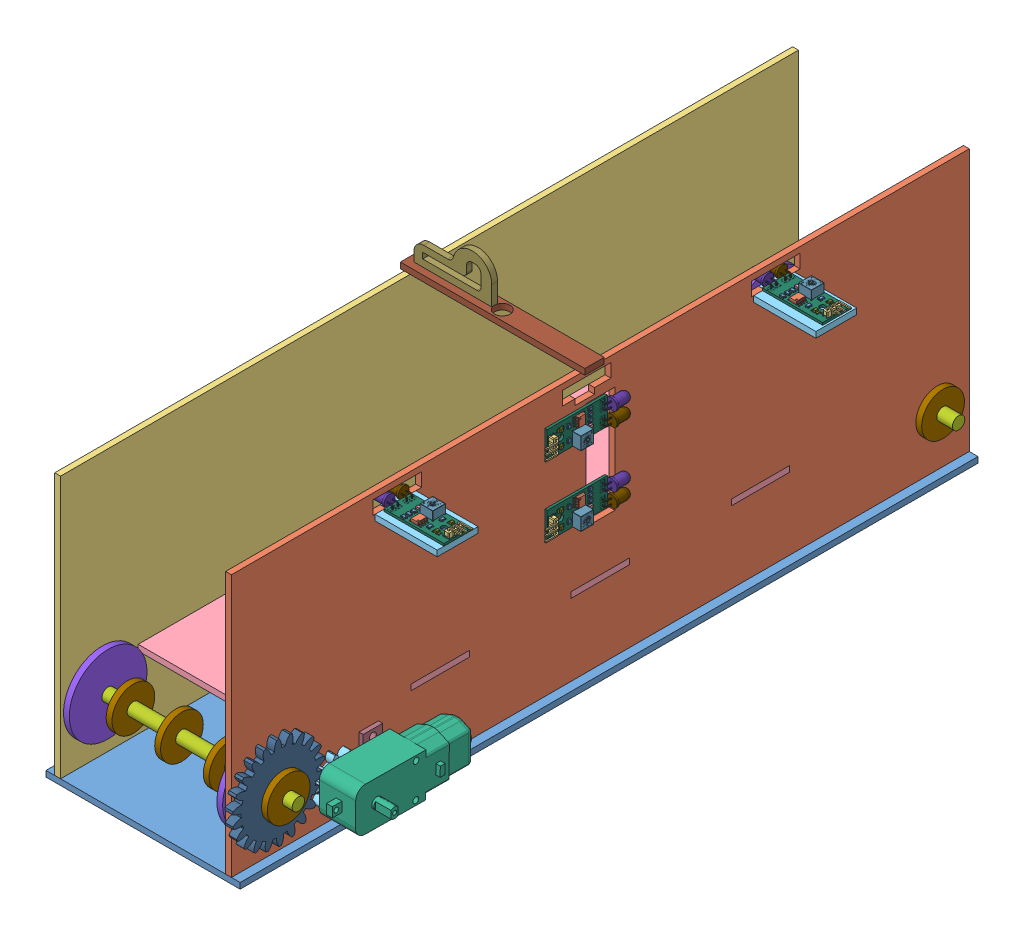
SolidWorks assembly EnsambleSoloIr, configuration Predeterminado. Lengths in mm.
Overall size (132.68 161.82 399.89).
100 component instances, 41 part files, 61 mates.
Components (placement in the parent):
- BAseGeneral-1: BAseGeneral [Predeterminado] at (-4.2266 -31.7563 350) size (100 3 380)
- ParedDerecha-2: ParedDerecha [Predeterminado] at (38.2734 38.7437 350) x (0 0 -1) z (1 0 0) size (380 138 3)
- ParedIzquierda-1: ParedIzquierda [Predeterminado] at (-46.7266 38.7437 350) x (0 0 1) z (-1 0 0) size (380 138 3)
- base-1: base [Predeterminado] at (-4.2266 8.2437 350) size (91 3 300)
- MiEngranePequeñoV2-1: MiEngranePequeñoV2 [Predeterminado] at (41.7734 384.4008 222.5284) x (0 -0.999961 0.008878) z (0 0.008878 0.999961) size (23.7 4 23.48)
- Motor-1: Motor [Predeterminado] at (65.5434 -8.5781 489.3215) x (0 -0.008878 -0.999961) z (0 0.999961 -0.008878) size (70.2 36.87 22.3)
- ejeRuedas-1: ejeRuedas [Predeterminado] at (55.7734 1.2437 520) x (0 1 0) z (0 0 1) size (6.4 110 6.4)
- RuedaGrande-1: RuedaGrande [Predeterminado] at (-42.2266 1.2437 520) x (0 1 0) z (0 0 1) size (40 3 40)
- RuedaGrande-2: RuedaGrande [Predeterminado] at (36.7734 1.2437 520) x (0 1 0) z (0 0 1) size (40 3 40)
- ruedaPequeña-1: ruedaPequeña [Predeterminado] at (-29.2266 1.2437 520) x (0 1 0) z (0 0 1) size (22 3 22)
- ruedaPequeña-2: ruedaPequeña [Predeterminado] at (-4.2266 1.2437 520) x (0 1 0) z (0 0 1) size (22 3 22)
- ruedaPequeña-3: ruedaPequeña [Predeterminado] at (20.7734 1.2437 520) x (0 1 0) z (0 0 1) size (22 3 22)
- EngraneGrande-1: EngraneGrande [Predeterminado] at (41.7734 -30.0906 1041.862) x (0 0.673646 -0.739054) z (1 0 0) size (48.01 47.68 4)
- ruedaPequeña-4: ruedaPequeña [Predeterminado] at (47.7734 1.2437 520) x (0 -1 0) z (0 0 1) size (22 3 22)
- ruedaPequeña-5: ruedaPequeña [Predeterminado] at (-53.2266 1.2437 520) x (0 -1 0) z (0 0 1) size (22 3 22)
- ejeRuedas-2: ejeRuedas [Predeterminado] at (55.7734 1.2437 180) x (0 1 0) z (0 0 1) size (6.4 110 6.4)
- ruedaPequeña-6: ruedaPequeña [Predeterminado] at (-50.2266 1.2437 180) x (0 1 0) z (0 0 1) size (22 3 22)
- ruedaPequeña-7: ruedaPequeña [Predeterminado] at (-4.2266 1.2437 180) x (0 1 0) z (0 0 1) size (22 3 22)
- ruedaPequeña-8: ruedaPequeña [Predeterminado] at (20.7734 1.2437 180) x (0 1 0) z (0 0 1) size (22 3 22)
- RuedaGrande-3: RuedaGrande [Predeterminado] at (-41.2266 1.2437 180) x (0 1 0) z (0 0 1) size (40 3 40)
- RuedaGrande-4: RuedaGrande [Predeterminado] at (32.7734 1.2437 180) x (0 -0.381849 0.924225) z (0 0.924225 0.381849) size (40 3 40)
- ruedaPequeña-9: ruedaPequeña [Predeterminado] at (47.7734 1.2437 180) x (0 1 0) z (0 0 1) size (22 3 22)
- ruedaPequeña-10: ruedaPequeña [Predeterminado] at (-29.2266 1.2437 180) x (0 1 0) z (0 0 1) size (22 3 22)
- Travesaño-1: Travesaño [Predeterminado] at (-4.2266 106.2437 355) size (95 3 10)
- GuiaMangera-1: GuiaMangera [Predeterminado] at (-28.1798 119.2437 353.5) size (40 23 3)
- SoporteMotor-1: SoporteMotor [Predeterminado] at (40.445 -8.7563 469.3) x (0 0 -1) z (1 0 0) size (10 24 3)
- Sensor_IR.stp-1: Sensor_IR.stp [Predeterminado] at (41.6734 48.2437 363.5) x (0 0 -1) z (1 0 0) size (45.22 14 7.87)
  - 3362P-1-102LF.stp-1: 3362P-1-102LF.stp [Predeterminado] at (0.5 -3.2 1.53) x (1 0 0) z (0 -1 0) size (6.6 7.58 6.6)
  - IR_Sensor_FC-51_1.stp-1: IR_Sensor_FC-51_1.stp [Predeterminado] at origin size (31 14 1.25)
  - KPTR-3216CGCK.stp-1: KPTR-3216CGCK.stp [Predeterminado] at (-8.7 3.8 1.45) x (1 0 0) z (0 0 -1) size (3.2 1.6 1.05)
  - KPTR-3216CGCK.stp-2: KPTR-3216CGCK.stp [Predeterminado] at (-8.7 -3.8 1.45) x (1 0 0) z (0 0 -1) size (3.2 1.6 1.05)
  - LED 5mm.stp-1: LED 5mm.stp [Predeterminado] at (15.74 3.64 3) x (0 1 0) z (1 0 0) size (5.5 6.7 11.78)
  - LED 5mm_foto.stp-1: LED 5mm_foto.stp [Predeterminado] at (15.74 -3.64 3) x (0 1 0) z (1 0 0) size (5.5 6.7 11.78)
  - RESC-0805.stp-1: RESC-0805.stp [Predeterminado] at (-4.525 -3.15 1.2) x (0 -1 0) z (0 0 1) size (2.1 1.35 0.6)
  - RESC-0805.stp-2: RESC-0805.stp [Predeterminado] at (-4.525 3.25 1.2) x (0 1 0) z (0 0 1) size (2.1 1.35 0.6)
  - SOIC8-150-50.stp-1: SOIC8-150-50.stp [Predeterminado] at (0.55 3.85 1.2) x (1 0 0) z (0 -1 0) size (6 1.91 4.9)
  - 1 Pin 2.54 mm Right Angle Single Row Pin Header Male 90 degrees Needle Connector.stp-1: 1 Pin 2.54 mm Right Angle Single Row Pin Header Male 90 degrees Needle Connector.stp [Predeterminado] at (-13.5 2.54 -1.76) x (-1 0 0) z (0 0 1) size (8.45 2.54 7.3)
  - 1 Pin 2.54 mm Right Angle Single Row Pin Header Male 90 degrees Needle Connector.stp-2: 1 Pin 2.54 mm Right Angle Single Row Pin Header Male 90 degrees Needle Connector.stp [Predeterminado] at (-13.5 0 -1.76) x (-1 0 0) z (0 0 1) size (8.45 2.54 7.3)
  - 1 Pin 2.54 mm Right Angle Single Row Pin Header Male 90 degrees Needle Connector.stp-3: 1 Pin 2.54 mm Right Angle Single Row Pin Header Male 90 degrees Needle Connector.stp [Predeterminado] at (-13.5 -2.54 -1.76) x (-1 0 0) z (0 0 1) size (8.45 2.54 7.3)
  - RESC-0805.stp-3: RESC-0805.stp [Predeterminado] at (6.45 5.625 1.2) size (2.1 1.35 0.6)
  - RESC-0805.stp-4: RESC-0805.stp [Predeterminado] at (6.45 3.085 1.2) size (2.1 1.35 0.6)
  - RESC-0805.stp-5: RESC-0805.stp [Predeterminado] at (6.45 0.545 1.2) size (2.1 1.35 0.6)
  - CAPC-0805-T0.95-BN.stp-1: CAPC-0805-T0.95-BN.stp [Predeterminado] at (6.45 -1.995 1.2) size (2.1 1.35 0.95)
  - CAPC-0805-T0.95-BN.stp-2: CAPC-0805-T0.95-BN.stp [Predeterminado] at (6.45 -4.535 1.2) size (2.1 1.35 0.95)
- Sensor_IR.stp-2: Sensor_IR.stp [Predeterminado] at (41.6734 84.2437 363.5) x (0 0 -1) z (1 0 0) size (45.22 14 7.87)
  - 3362P-1-102LF.stp-1: 3362P-1-102LF.stp [Predeterminado] at (0.5 -3.2 1.53) x (1 0 0) z (0 -1 0) size (6.6 7.58 6.6)
  - IR_Sensor_FC-51_1.stp-1: IR_Sensor_FC-51_1.stp [Predeterminado] at origin size (31 14 1.25)
  - KPTR-3216CGCK.stp-1: KPTR-3216CGCK.stp [Predeterminado] at (-8.7 3.8 1.45) x (1 0 0) z (0 0 -1) size (3.2 1.6 1.05)
  - KPTR-3216CGCK.stp-2: KPTR-3216CGCK.stp [Predeterminado] at (-8.7 -3.8 1.45) x (1 0 0) z (0 0 -1) size (3.2 1.6 1.05)
  - LED 5mm.stp-1: LED 5mm.stp [Predeterminado] at (15.74 3.64 3) x (0 1 0) z (1 0 0) size (5.5 6.7 11.78)
  - LED 5mm_foto.stp-1: LED 5mm_foto.stp [Predeterminado] at (15.74 -3.64 3) x (0 1 0) z (1 0 0) size (5.5 6.7 11.78)
  - RESC-0805.stp-1: RESC-0805.stp [Predeterminado] at (-4.525 -3.15 1.2) x (0 -1 0) z (0 0 1) size (2.1 1.35 0.6)
  - RESC-0805.stp-2: RESC-0805.stp [Predeterminado] at (-4.525 3.25 1.2) x (0 1 0) z (0 0 1) size (2.1 1.35 0.6)
  - SOIC8-150-50.stp-1: SOIC8-150-50.stp [Predeterminado] at (0.55 3.85 1.2) x (1 0 0) z (0 -1 0) size (6 1.91 4.9)
  - 1 Pin 2.54 mm Right Angle Single Row Pin Header Male 90 degrees Needle Connector.stp-1: 1 Pin 2.54 mm Right Angle Single Row Pin Header Male 90 degrees Needle Connector.stp [Predeterminado] at (-13.5 2.54 -1.76) x (-1 0 0) z (0 0 1) size (8.45 2.54 7.3)
  - 1 Pin 2.54 mm Right Angle Single Row Pin Header Male 90 degrees Needle Connector.stp-2: 1 Pin 2.54 mm Right Angle Single Row Pin Header Male 90 degrees Needle Connector.stp [Predeterminado] at (-13.5 0 -1.76) x (-1 0 0) z (0 0 1) size (8.45 2.54 7.3)
  - 1 Pin 2.54 mm Right Angle Single Row Pin Header Male 90 degrees Needle Connector.stp-3: 1 Pin 2.54 mm Right Angle Single Row Pin Header Male 90 degrees Needle Connector.stp [Predeterminado] at (-13.5 -2.54 -1.76) x (-1 0 0) z (0 0 1) size (8.45 2.54 7.3)
  - RESC-0805.stp-3: RESC-0805.stp [Predeterminado] at (6.45 5.625 1.2) size (2.1 1.35 0.6)
  - RESC-0805.stp-4: RESC-0805.stp [Predeterminado] at (6.45 3.085 1.2) size (2.1 1.35 0.6)
  - RESC-0805.stp-5: RESC-0805.stp [Predeterminado] at (6.45 0.545 1.2) size (2.1 1.35 0.6)
  - CAPC-0805-T0.95-BN.stp-1: CAPC-0805-T0.95-BN.stp [Predeterminado] at (6.45 -1.995 1.2) size (2.1 1.35 0.95)
  - CAPC-0805-T0.95-BN.stp-2: CAPC-0805-T0.95-BN.stp [Predeterminado] at (6.45 -4.535 1.2) size (2.1 1.35 0.95)
- SoporteIrHorizontal-1: SoporteIrHorizontal [Predeterminado] at (38.2734 93.2437 460.5) x (0 0 -1) z (1 0 0) size (21 3 35)
- SoporteIrHorizontal-2: SoporteIrHorizontal [Predeterminado] at (38.2734 93.2437 265.5) x (0 0 -1) z (1 0 0) size (21 3 35)
- Sensor_IR.stp-3: Sensor_IR.stp [Predeterminado] at (57.7734 97.2437 260.5) x (-1 0 0) z (0 1 0) size (45.22 14 7.87)
  - 3362P-1-102LF.stp-1: 3362P-1-102LF.stp [Predeterminado] at (0.5 -3.2 1.53) x (1 0 0) z (0 -1 0) size (6.6 7.58 6.6)
  - IR_Sensor_FC-51_1.stp-1: IR_Sensor_FC-51_1.stp [Predeterminado] at origin size (31 14 1.25)
  - KPTR-3216CGCK.stp-1: KPTR-3216CGCK.stp [Predeterminado] at (-8.7 3.8 1.45) x (1 0 0) z (0 0 -1) size (3.2 1.6 1.05)
  - KPTR-3216CGCK.stp-2: KPTR-3216CGCK.stp [Predeterminado] at (-8.7 -3.8 1.45) x (1 0 0) z (0 0 -1) size (3.2 1.6 1.05)
  - LED 5mm.stp-1: LED 5mm.stp [Predeterminado] at (15.74 3.64 3) x (0 1 0) z (1 0 0) size (5.5 6.7 11.78)
  - LED 5mm_foto.stp-1: LED 5mm_foto.stp [Predeterminado] at (15.74 -3.64 3) x (0 1 0) z (1 0 0) size (5.5 6.7 11.78)
  - RESC-0805.stp-1: RESC-0805.stp [Predeterminado] at (-4.525 -3.15 1.2) x (0 -1 0) z (0 0 1) size (2.1 1.35 0.6)
  - RESC-0805.stp-2: RESC-0805.stp [Predeterminado] at (-4.525 3.25 1.2) x (0 1 0) z (0 0 1) size (2.1 1.35 0.6)
  - SOIC8-150-50.stp-1: SOIC8-150-50.stp [Predeterminado] at (0.55 3.85 1.2) x (1 0 0) z (0 -1 0) size (6 1.91 4.9)
  - 1 Pin 2.54 mm Right Angle Single Row Pin Header Male 90 degrees Needle Connector.stp-1: 1 Pin 2.54 mm Right Angle Single Row Pin Header Male 90 degrees Needle Connector.stp [Predeterminado] at (-13.5 2.54 -1.76) x (-1 0 0) z (0 0 1) size (8.45 2.54 7.3)
  - 1 Pin 2.54 mm Right Angle Single Row Pin Header Male 90 degrees Needle Connector.stp-2: 1 Pin 2.54 mm Right Angle Single Row Pin Header Male 90 degrees Needle Connector.stp [Predeterminado] at (-13.5 0 -1.76) x (-1 0 0) z (0 0 1) size (8.45 2.54 7.3)
  - 1 Pin 2.54 mm Right Angle Single Row Pin Header Male 90 degrees Needle Connector.stp-3: 1 Pin 2.54 mm Right Angle Single Row Pin Header Male 90 degrees Needle Connector.stp [Predeterminado] at (-13.5 -2.54 -1.76) x (-1 0 0) z (0 0 1) size (8.45 2.54 7.3)
  - RESC-0805.stp-3: RESC-0805.stp [Predeterminado] at (6.45 5.625 1.2) size (2.1 1.35 0.6)
  - RESC-0805.stp-4: RESC-0805.stp [Predeterminado] at (6.45 3.085 1.2) size (2.1 1.35 0.6)
  - RESC-0805.stp-5: RESC-0805.stp [Predeterminado] at (6.45 0.545 1.2) size (2.1 1.35 0.6)
  - CAPC-0805-T0.95-BN.stp-1: CAPC-0805-T0.95-BN.stp [Predeterminado] at (6.45 -1.995 1.2) size (2.1 1.35 0.95)
  - CAPC-0805-T0.95-BN.stp-2: CAPC-0805-T0.95-BN.stp [Predeterminado] at (6.45 -4.535 1.2) size (2.1 1.35 0.95)
- Sensor_IR.stp-4: Sensor_IR.stp [Predeterminado] at (57.7734 96.2437 455.4997) x (-1 0 -0.000038) z (0 1 0) size (45.22 14 7.87)
  - 3362P-1-102LF.stp-1: 3362P-1-102LF.stp [Predeterminado] at (0.5 -3.2 1.53) x (1 0 0) z (0 -1 0) size (6.6 7.58 6.6)
  - IR_Sensor_FC-51_1.stp-1: IR_Sensor_FC-51_1.stp [Predeterminado] at origin size (31 14 1.25)
  - KPTR-3216CGCK.stp-1: KPTR-3216CGCK.stp [Predeterminado] at (-8.7 3.8 1.45) x (1 0 0) z (0 0 -1) size (3.2 1.6 1.05)
  - KPTR-3216CGCK.stp-2: KPTR-3216CGCK.stp [Predeterminado] at (-8.7 -3.8 1.45) x (1 0 0) z (0 0 -1) size (3.2 1.6 1.05)
  - LED 5mm.stp-1: LED 5mm.stp [Predeterminado] at (15.74 3.64 3) x (0 1 0) z (1 0 0) size (5.5 6.7 11.78)
  - LED 5mm_foto.stp-1: LED 5mm_foto.stp [Predeterminado] at (15.74 -3.64 3) x (0 1 0) z (1 0 0) size (5.5 6.7 11.78)
  - RESC-0805.stp-1: RESC-0805.stp [Predeterminado] at (-4.525 -3.15 1.2) x (0 -1 0) z (0 0 1) size (2.1 1.35 0.6)
  - RESC-0805.stp-2: RESC-0805.stp [Predeterminado] at (-4.525 3.25 1.2) x (0 1 0) z (0 0 1) size (2.1 1.35 0.6)
  - SOIC8-150-50.stp-1: SOIC8-150-50.stp [Predeterminado] at (0.55 3.85 1.2) x (1 0 0) z (0 -1 0) size (6 1.91 4.9)
  - 1 Pin 2.54 mm Right Angle Single Row Pin Header Male 90 degrees Needle Connector.stp-1: 1 Pin 2.54 mm Right Angle Single Row Pin Header Male 90 degrees Needle Connector.stp [Predeterminado] at (-13.5 2.54 -1.76) x (-1 0 0) z (0 0 1) size (8.45 2.54 7.3)
  - 1 Pin 2.54 mm Right Angle Single Row Pin Header Male 90 degrees Needle Connector.stp-2: 1 Pin 2.54 mm Right Angle Single Row Pin Header Male 90 degrees Needle Connector.stp [Predeterminado] at (-13.5 0 -1.76) x (-1 0 0) z (0 0 1) size (8.45 2.54 7.3)
  - 1 Pin 2.54 mm Right Angle Single Row Pin Header Male 90 degrees Needle Connector.stp-3: 1 Pin 2.54 mm Right Angle Single Row Pin Header Male 90 degrees Needle Connector.stp [Predeterminado] at (-13.5 -2.54 -1.76) x (-1 0 0) z (0 0 1) size (8.45 2.54 7.3)
  - RESC-0805.stp-3: RESC-0805.stp [Predeterminado] at (6.45 5.625 1.2) size (2.1 1.35 0.6)
  - RESC-0805.stp-4: RESC-0805.stp [Predeterminado] at (6.45 3.085 1.2) size (2.1 1.35 0.6)
  - RESC-0805.stp-5: RESC-0805.stp [Predeterminado] at (6.45 0.545 1.2) size (2.1 1.35 0.6)
  - CAPC-0805-T0.95-BN.stp-1: CAPC-0805-T0.95-BN.stp [Predeterminado] at (6.45 -1.995 1.2) size (2.1 1.35 0.95)
  - CAPC-0805-T0.95-BN.stp-2: CAPC-0805-T0.95-BN.stp [Predeterminado] at (6.45 -4.535 1.2) size (2.1 1.35 0.95)
Mates (geometry in assembly coordinates):
- Coincidente2: coincident anti-aligned: plane of BAseGeneral-1 through (41.2734 -28.7563 417.5) normal (-1 0 0); plane of ParedDerecha-2 through (41.2734 38.7437 350) normal (1 0 0)
- Coincidente4: coincident anti-aligned: plane of BAseGeneral-1 through (38.2734 -28.7563 447.5) normal (0 0 -1); plane of ParedDerecha-2 through (41.2734 38.7437 447.5) normal (0 0 1)
- Coincidente5: coincident aligned: plane of BAseGeneral-1 through (-4.2266 -31.7563 350) normal (0 -1 0); plane of ParedDerecha-2 through (41.2734 -31.7563 350) normal (0 -1 0)
- Coincidente6: coincident anti-aligned: plane of BAseGeneral-1 through (-49.7266 -28.7563 417.5) normal (1 0 0); plane of ParedIzquierda-1 through (-49.7266 38.7437 350) normal (-1 0 0)
- Coincidente7: coincident anti-aligned: plane of BAseGeneral-1 through (-49.7266 -28.7563 447.5) normal (0 0 -1); plane of ParedIzquierda-1 through (-49.7266 -31.7563 447.5) normal (0 0 1)
- Coincidente8: coincident aligned: plane of BAseGeneral-1 through (-4.2266 -31.7563 350) normal (0 -1 0); plane of ParedIzquierda-1 through (-49.7266 -31.7563 335) normal (0 -1 0)
- Coincidente9: coincident aligned: plane of ParedDerecha-2 through (41.2734 38.7437 350) normal (1 0 0); plane of base-1 through (41.2734 11.2437 447.5) normal (1 0 0)
- Coincidente10: coincident anti-aligned: plane of ParedDerecha-2 through (41.2734 38.7437 447.5) normal (0 0 -1); plane of base-1 through (38.2734 11.2437 447.5) normal (0 0 1)
- Coincidente11: coincident anti-aligned: plane of ParedDerecha-2 through (41.2734 11.2437 350) normal (0 -1 0); plane of base-1 through (-4.2266 11.2437 350) normal (0 1 0)
- Coincidente23: coincident anti-aligned: plane of MiEngranePequeñoV2-1 through (45.7734 386.7548 487.6616) normal (0 -0.008878 -0.999961); plane of Motor-1 through (45.7734 -8.5617 491.1715) normal (0 0.008878 0.999961)
- Coincidente24: coincident anti-aligned: plane of MiEngranePequeñoV2-1 through (45.7734 384.4008 222.5284) normal (1 0 0); plane of Motor-1 through (45.7734 -8.5781 489.3215) normal (-1 0 0)
- Coincidente26: coincident aligned: line of MiEngranePequeñoV2-1 through (45.7734 -10.4938 491.1886) axis (-1 0 0); line of Motor-1 through (45.7734 -10.4938 491.1886) axis (-1 0 0)
- Coincidente27: coincident anti-aligned: cylinder of ejeRuedas-1 through (-54.2266 1.2437 520) axis (1 0 0) radius 3.2; circle of RuedaGrande-1
- Concéntrica7: concentric aligned: cylinder of ejeRuedas-1 through (-54.2266 1.2437 520) axis (1 0 0) radius 3.2; cylinder of RuedaGrande-2 through (33.7734 1.2437 520) axis (1 0 0) radius 3.2
- Distancia2: distance = 9 mm aligned: plane of RuedaGrande-1 through (-45.2266 1.2437 520) normal (-1 0 0); plane of ejeRuedas-1 through (-54.2266 1.2437 520) normal (-1 0 0)
- Distancia3: distance = 19 mm aligned: plane of RuedaGrande-2 through (36.7734 1.2437 520) normal (1 0 0); plane of ejeRuedas-1 through (55.7734 1.2437 520) normal (1 0 0)
- Concéntrica8: concentric aligned: cylinder of ejeRuedas-1 through (-54.2266 1.2437 520) axis (1 0 0) radius 3.2; cylinder of ruedaPequeña-1 through (-32.2266 1.2437 520) axis (1 0 0) radius 3.2
- Distancia4: distance = 85 mm aligned: plane of ruedaPequeña-1 through (-29.2266 1.2437 520) normal (1 0 0); plane of ejeRuedas-1 through (55.7734 1.2437 520) normal (1 0 0)
- Concéntrica9: concentric aligned: cylinder of ejeRuedas-1 through (-54.2266 1.2437 520) axis (1 0 0) radius 3.2; cylinder of ruedaPequeña-2 through (-7.2266 1.2437 520) axis (1 0 0) radius 3.2
- Distancia5: distance = 60 mm aligned: plane of ruedaPequeña-2 through (-4.2266 1.2437 520) normal (1 0 0); plane of ejeRuedas-1 through (55.7734 1.2437 520) normal (1 0 0)
- Concéntrica10: concentric aligned: cylinder of ejeRuedas-1 through (-54.2266 1.2437 520) axis (1 0 0) radius 3.2; cylinder of ruedaPequeña-3 through (17.7734 1.2437 520) axis (1 0 0) radius 3.2
- Distancia6: distance = 35 mm aligned: plane of ruedaPequeña-3 through (20.7734 1.2437 520) normal (1 0 0); plane of ejeRuedas-1 through (55.7734 1.2437 520) normal (1 0 0)
- Concéntrica11: concentric anti-aligned: cylinder of ParedDerecha-2 through (41.2734 1.2437 520) axis (-1 0 0) radius 3.5; cylinder of ejeRuedas-1 through (-54.2266 1.2437 520) axis (1 0 0) radius 3.2
- Tangente3: tangent anti-aligned: cylinder of ejeRuedas-1 through (-54.2266 1.2437 520) axis (1 0 0) radius 3.2; face of EngraneGrande-1
- Distancia7: distance = 10 mm aligned: plane of ejeRuedas-1 through (55.7734 1.2437 520) normal (1 0 0); plane of EngraneGrande-1 through (45.7734 -20.0408 514.8334) normal (1 0 0)
- Coincidente38: coincident aligned: plane of MiEngranePequeñoV2-1 through (45.7734 384.4008 222.5284) normal (1 0 0); plane of EngraneGrande-1 through (45.7734 -20.0408 514.8334) normal (1 0 0)
- Concéntrica12: concentric aligned: cylinder of ParedDerecha-2 through (41.2734 -17.5063 469.3) axis (-1 0 0) radius 2; cylinder of Motor-1 through (74.6434 -17.5063 469.3) axis (-1 0 0) radius 1.5
- Paralelo3: parallel aligned: cylinder of ParedDerecha-2 through (41.2734 -0.0063 469.3) axis (-1 0 0) radius 2; cylinder of Motor-1 through (74.6434 -0.0069 469.1446) axis (-1 0 0) radius 1.5
- Coincidente39: coincident aligned: plane of BAseGeneral-1 through (-54.2266 -28.7563 540) normal (-1 0 0); plane of ejeRuedas-1 through (-54.2266 1.2437 520) normal (-1 0 0)
- Concéntrica14: concentric anti-aligned: cylinder of ejeRuedas-1 through (-54.2266 1.2437 520) axis (1 0 0) radius 3.2; cylinder of ruedaPequeña-4 through (50.7734 1.2437 520) axis (-1 0 0) radius 3.2
- Distancia8: distance = 5 mm aligned: plane of ruedaPequeña-4 through (50.7734 1.2437 520) normal (1 0 0); plane of ejeRuedas-1 through (55.7734 1.2437 520) normal (1 0 0)
- Concéntrica16: concentric anti-aligned: cylinder of ejeRuedas-1 through (-54.2266 1.2437 520) axis (1 0 0) radius 3.2; cylinder of ruedaPequeña-5 through (-50.2266 1.2437 520) axis (-1 0 0) radius 3.2
- Distancia9: distance = 1 mm aligned: plane of ruedaPequeña-5 through (-53.2266 1.2437 520) normal (-1 0 0); plane of ejeRuedas-1 through (-54.2266 1.2437 520) normal (-1 0 0)
- Concéntrica17: concentric aligned: cylinder of ejeRuedas-2 through (-54.2266 1.2437 180) axis (1 0 0) radius 3.2; cylinder of ruedaPequeña-10 through (-32.2266 1.2437 180) axis (1 0 0) radius 3.2
- Concéntrica18: concentric anti-aligned: cylinder of ejeRuedas-2 through (-54.2266 1.2437 180) axis (1 0 0) radius 3.2; cylinder of RuedaGrande-4 through (35.7734 1.2437 180) axis (-1 0 0) radius 3.2
- Coincidente42: coincident anti-aligned: cylinder of ejeRuedas-2 through (-54.2266 1.2437 180) axis (1 0 0) radius 3.2; circle of ruedaPequeña-8
- Concéntrica19: concentric aligned: cylinder of ejeRuedas-2 through (-54.2266 1.2437 180) axis (1 0 0) radius 3.2; cylinder of ruedaPequeña-7 through (-7.2266 1.2437 180) axis (1 0 0) radius 3.2
- Concéntrica20: concentric aligned: cylinder of ejeRuedas-2 through (-54.2266 1.2437 180) axis (1 0 0) radius 3.2; cylinder of ruedaPequeña-6 through (-53.2266 1.2437 180) axis (1 0 0) radius 3.2
- Concéntrica21: concentric aligned: cylinder of ejeRuedas-2 through (-54.2266 1.2437 180) axis (1 0 0) radius 3.2; cylinder of RuedaGrande-3 through (-44.2266 1.2437 180) axis (1 0 0) radius 3.2
- Concéntrica22: concentric aligned: cylinder of ejeRuedas-2 through (-54.2266 1.2437 180) axis (1 0 0) radius 3.2; cylinder of ruedaPequeña-9 through (44.7734 1.2437 180) axis (1 0 0) radius 3.2
- Concéntrica23: concentric anti-aligned: circle of ParedIzquierda-1; cylinder of ejeRuedas-2 through (-54.2266 1.2437 180) axis (1 0 0) radius 3.2
- Coincidente43: coincident aligned: plane of BAseGeneral-1 through (-54.2266 -28.7563 540) normal (-1 0 0); plane of ejeRuedas-2 through (-54.2266 1.2437 180) normal (-1 0 0)
- Distancia10: distance = 97 mm aligned: plane of RuedaGrande-3 through (-41.2266 1.2437 180) normal (1 0 0); plane of ejeRuedas-2 through (55.7734 1.2437 180) normal (1 0 0)
- Distancia11: distance = 23 mm anti-aligned: plane of ejeRuedas-2 through (55.7734 1.2437 180) normal (1 0 0); plane of RuedaGrande-4 through (32.7734 1.2437 180) normal (-1 0 0)
- Distancia12: distance = 106 mm aligned: plane of ruedaPequeña-6 through (-50.2266 1.2437 180) normal (1 0 0); plane of ejeRuedas-2 through (55.7734 1.2437 180) normal (1 0 0)
- Distancia13: distance = 35 mm aligned: plane of ruedaPequeña-8 through (20.7734 1.2437 180) normal (1 0 0); plane of ejeRuedas-2 through (55.7734 1.2437 180) normal (1 0 0)
- Distancia14: distance = 60 mm aligned: plane of ruedaPequeña-7 through (-4.2266 1.2437 180) normal (1 0 0); plane of ejeRuedas-2 through (55.7734 1.2437 180) normal (1 0 0)
- Distancia15: distance = 85 mm aligned: plane of ruedaPequeña-10 through (-29.2266 1.2437 180) normal (1 0 0); plane of ejeRuedas-2 through (55.7734 1.2437 180) normal (1 0 0)
- Distancia16: distance = 8 mm aligned: plane of ruedaPequeña-9 through (47.7734 1.2437 180) normal (1 0 0); plane of ejeRuedas-2 through (55.7734 1.2437 180) normal (1 0 0)
- Coincidente51: coincident anti-aligned: plane of ParedDerecha-2 through (41.2734 106.2437 350) normal (0 1 0); plane of Travesaño-1 through (-4.2266 106.2437 355) normal (0 -1 0)
- Distancia17: distance = 2 mm aligned: plane of Travesaño-1 through (43.2734 109.2437 360) normal (1 0 0); plane of ParedDerecha-2 through (41.2734 38.7437 350) normal (1 0 0)
- Distancia18: distance = 190 mm aligned: plane of Travesaño-1 through (-51.7266 109.2437 350) normal (0 0 -1); plane of ParedDerecha-2 through (41.2734 38.7437 160) normal (0 0 -1)
- Coincidente54: coincident anti-aligned: plane of Travesaño-1 through (-43.7266 109.2437 356.5) normal (0 0 -1); plane of GuiaMangera-1 through (-18.1798 119.2437 356.5) normal (0 0 1)
- Coincidente55: coincident anti-aligned: plane of Travesaño-1 through (-43.7266 109.2437 356.5) normal (1 0 0); plane of GuiaMangera-1 through (-43.7266 109.2437 356.5) normal (-1 0 0)
- Coincidente56: coincident aligned: plane of Travesaño-1 through (-4.2266 106.2437 355) normal (0 -1 0); plane of GuiaMangera-1 through (-43.7266 106.2437 356.5) normal (0 -1 0)
- Concéntrica24: concentric anti-aligned: cylinder of ParedDerecha-2 through (41.2734 -0.0063 469.3) axis (-1 0 0) radius 2; circle of SoporteMotor-1
- Concéntrica25: concentric aligned: cylinder of ParedDerecha-2 through (41.2734 -17.5063 469.3) axis (-1 0 0) radius 2; cylinder of SoporteMotor-1 through (43.445 -17.5063 469.3) axis (-1 0 0) radius 1.75
- Distancia19: distance = 0.4 mm anti-aligned: plane of Sensor_IR.stp-2/IR_Sensor_FC-51_1.stp-1 through (41.6734 84.2437 363.5) normal (-1 0 0); plane of ParedDerecha-2 through (41.2734 38.7437 350) normal (1 0 0)
- Coincidente59: coincident aligned: cylinder of ParedDerecha-2 through (41.2734 84.2437 372) axis (-1 0 0) radius 1.5; circle of Sensor_IR.stp-2/IR_Sensor_FC-51_1.stp-1
- Distancia20: distance = 0.4 mm anti-aligned: plane of Sensor_IR.stp-1/IR_Sensor_FC-51_1.stp-1 through (41.6734 48.2437 363.5) normal (-1 0 0); plane of ParedDerecha-2 through (41.2734 38.7437 350) normal (1 0 0)
- Concéntrica26: concentric anti-aligned: cylinder of ParedDerecha-2 through (41.2734 48.2437 372) axis (-1 0 0) radius 1.5; cylinder of Sensor_IR.stp-1/IR_Sensor_FC-51_1.stp-1 through (41.6734 48.2437 372) axis (1 0 0) radius 1.5
